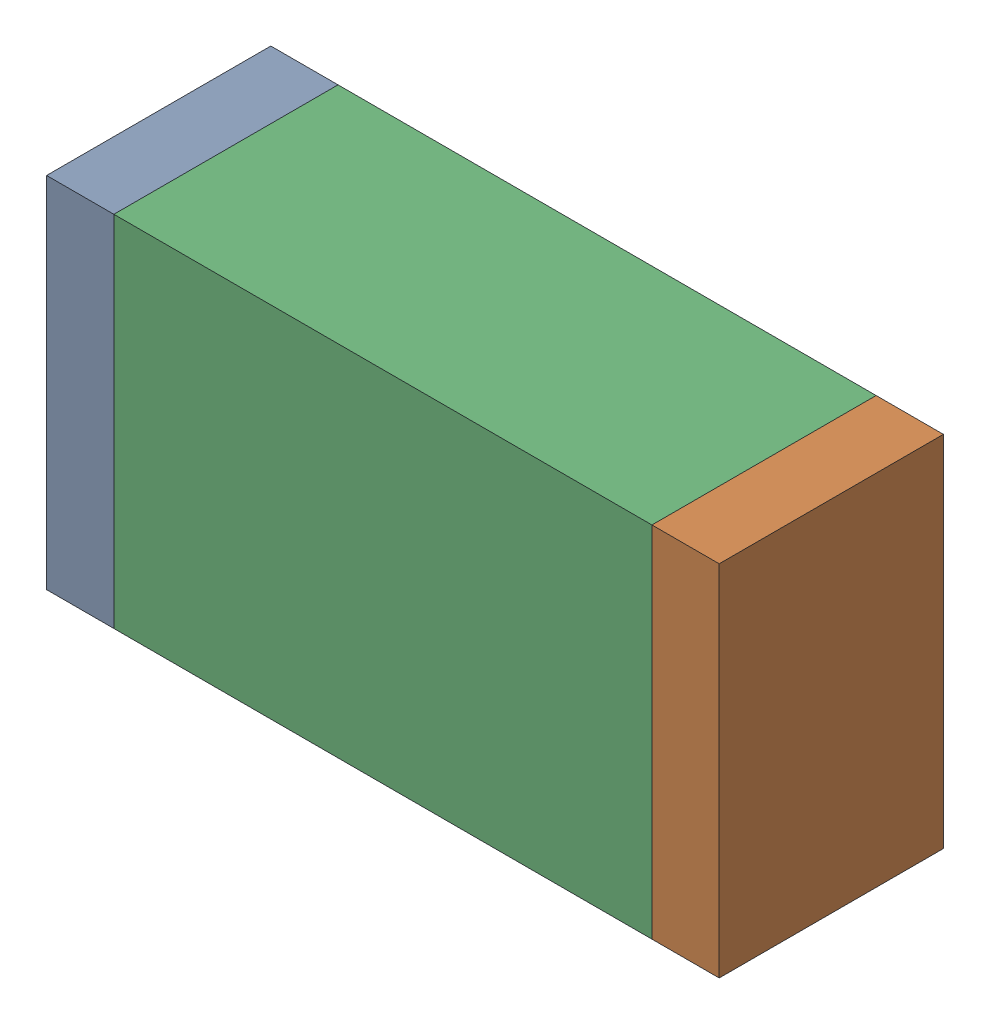
SolidWorks assembly R22, configuration Default. Lengths in mm.
Overall size (1.5 0.8 0.5).
6 component instances, 2 part files, 0 mates.
Components (placement in the parent):
- 836752496-1: 836752496 [Default] at (129.225 43.1 0) size (0.15 0.8 0.5)
  - Extruded_2-1: Extruded_2 [Default] at origin size (0.15 0.8 0.5)
- 836752496-2: 836752496 [Default] at (130.575 43.1 0) size (0.15 0.8 0.5)
  - Extruded_2-1: Extruded_2 [Default] at origin size (0.15 0.8 0.5)
- 836752368-1: 836752368 [Default] at (129.9 43.1 0) size (1.2 0.8 0.5)
  - Extruded-1: Extruded [Default] at origin size (1.2 0.8 0.5)
